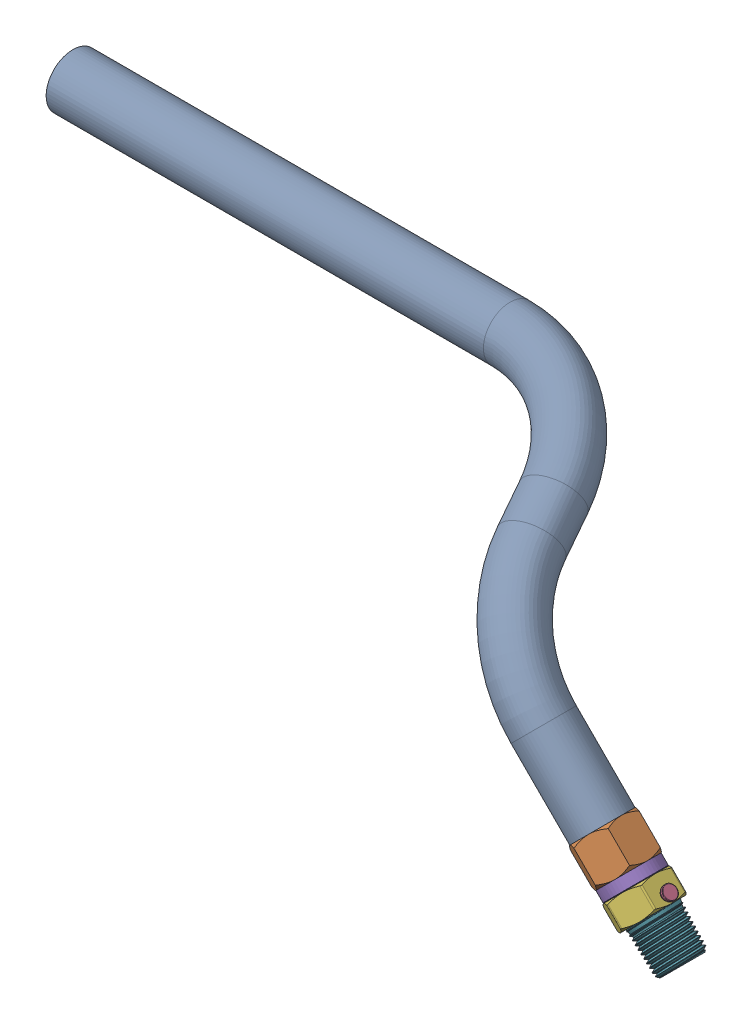
SolidWorks assembly Hose, configuration Default. Lengths in mm.
Overall size (389.31 153.94 115.18).
2 component instances, 2 part files, 2 mates.
Components (placement in the parent):
- Hose-1: Hose [Default] at (791.0572 841.5637 1353.3919) size (348.92 115.35 113.22)
- 5273K21_Threaded Hose Fitting for Water-1: 5273K21_Threaded Hose Fitting for Water [5273K21] at (810.1403 822.4806 1353.3919) x (0.707107 -0.707107 0) z (0 0 1) size (54.87 27.94 29.33)
Mates (geometry in assembly coordinates):
- Concentric1: concentric anti-aligned: cylinder of Hose-1 through (791.0572 841.5637 1353.3919) axis (-0.707107 0.707107 0) radius 12.7; cylinder of 5273K21_Threaded Hose Fitting for Water-1 through (803.5129 829.1081 1353.3919) axis (0.707107 -0.707107 0) radius 12.7
- Coincident1: coincident anti-aligned: plane of Hose-1 through (791.0572 841.5637 1353.3919) normal (0.707107 -0.707107 0); plane of 5273K21_Threaded Hose Fitting for Water-1 through (791.0572 841.5637 1353.3919) normal (-0.707107 0.707107 0)
